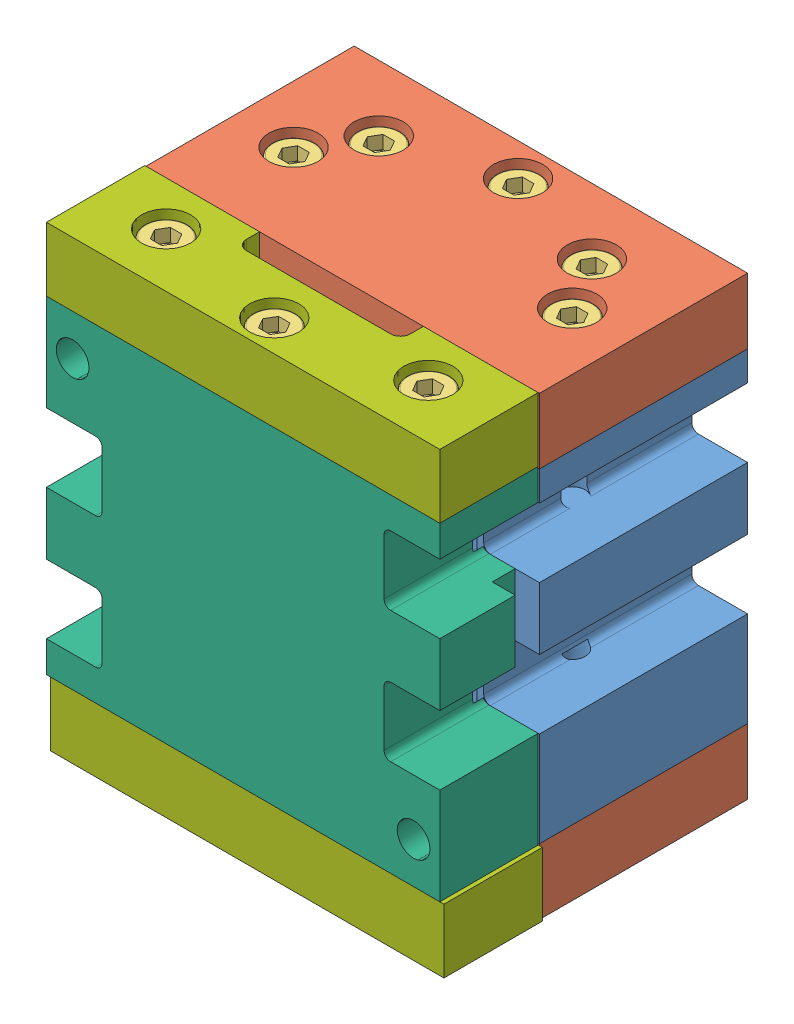
SolidWorks assembly ГТК СБ 00.00.00 Матрица, configuration По умолчанию. Lengths in mm.
Overall size (121.25 139 93.5).
28 component instances, 7 part files, 3 mates.
Components (placement in the parent):
- ГТК 01.01.00 Сборка пресс-формы-1: ГТК 01.01.00 Сборка пресс-формы [По умолчанию] at origin size (120 139 88.5)
  - ГТК 01.01.01 Матрица-1: ГТК 01.01.01 Матрица [По умолчанию] at origin size (120 99 63.5)
  - ГТК 01.01.02 Боковина пресс-формы-1: ГТК 01.01.02 Боковина пресс-формы [По умолчанию] at (0 -49.5 31.75) x (1 0 0) z (0 -1 0) size (120 63.5 20)
  - ISO 4762 М8x16-1: ISO 4762 М8x16 [ISO 4762 M8 x 16 - 16N] at (-42.5 -67.5 36) x (0 1 0) z (0 0 1) size (24 13 13)
  - ISO 4762 М8x16-2: ISO 4762 М8x16 [ISO 4762 M8 x 16 - 16N] at (-32.5 -67.5 20) x (0 1 0) z (0 0 1) size (24 13 13)
  - ISO 4762 М8x16-3: ISO 4762 М8x16 [ISO 4762 M8 x 16 - 16N] at (0 -67.5 10) x (0 1 0) z (0 0 1) size (24 13 13)
  - ISO 4762 М8x16-4: ISO 4762 М8x16 [ISO 4762 M8 x 16 - 16N] at (32.5 -67.5 20) x (0 1 0) z (0 0 1) size (24 13 13)
  - ISO 4762 М8x16-5: ISO 4762 М8x16 [ISO 4762 M8 x 16 - 16N] at (42.5 -67.5 36) x (0 1 0) z (0 0 1) size (24 13 13)
  - ISO 4762 М8x16-11: ISO 4762 М8x16 [ISO 4762 M8 x 16 - 16N] at (-42.5 67.5 36) x (0 -1 0) z (0 0 1) size (24 13 13)
  - ISO 4762 М8x16-12: ISO 4762 М8x16 [ISO 4762 M8 x 16 - 16N] at (-32.5 67.5 20) x (0 -1 0) z (0 0 1) size (24 13 13)
  - ISO 4762 М8x16-13: ISO 4762 М8x16 [ISO 4762 M8 x 16 - 16N] at (0 67.5 10) x (0 -1 0) z (0 0 1) size (24 13 13)
  - ISO 4762 М8x16-14: ISO 4762 М8x16 [ISO 4762 M8 x 16 - 16N] at (32.5 67.5 20) x (0 -1 0) z (0 0 1) size (24 13 13)
  - ISO 4762 М8x16-15: ISO 4762 М8x16 [ISO 4762 M8 x 16 - 16N] at (42.5 67.5 36) x (0 -1 0) z (0 0 1) size (24 13 13)
  - ГТК 01.01.02 Боковина пресс-формы-3: ГТК 01.01.02 Боковина пресс-формы [По умолчанию] at (0 49.5 31.75) x (-1 0 0) z (0 1 0) size (120 63.5 20)
  - ГТК 01.01.03 Направляющая-1: ГТК 01.01.03 Направляющая [По умолчанию] at (-52.375 37.5 33.5) x (0 0 1) z (-0.953769 -0.300541 0) size (55 10 10)
  - ГТК 01.01.03 Направляющая-2: ГТК 01.01.03 Направляющая [По умолчанию] at (51.625 -37.5 33.5) x (0 0 1) z (-0.599492 0.800381 0) size (55 10 10)
  - ГТК 01.01.04 Втулка-1: ГТК 01.01.04 Втулка [По умолчанию] at (0 27 30) x (0 0 1) z (-0.845392 0.534146 0) size (36.5 12 12)
  - ГТК 01.01.04 Втулка-2: ГТК 01.01.04 Втулка [По умолчанию] at (0 -27 30) x (0 0 1) z (-0.844306 0.535861 0) size (36.5 12 12)
- ГТК 01.02.00 Сборка пуансона-1: ГТК 01.02.00 Сборка пуансона [По умолчанию] at (-60.375 -50 63.5) size (121.25 139 30.34)
  - ГТК 01.02.01 Пуансон-1: ГТК 01.02.01 Пуансон [По умолчанию] at origin size (120 100 30)
  - ГТК 02.01.02 Боковина Пуансона-1: ГТК 02.01.02 Боковина Пуансона [По умолчанию] at (121.25 0 30) x (-1 0 0) z (0 -1 0) size (120 30.34 139)
  - ГТК 02.01.02 Боковина Пуансона-2: ГТК 02.01.02 Боковина Пуансона [По умолчанию] at (0 100 30) x (1 0 0) z (0 1 0) size (120 30.34 139)
  - ISO 4762 М8x16-2: ISO 4762 М8x16 [ISO 4762 M8 x 16 - 16N] at (101.25 -17.5 13.5) x (0 1 0) z (0 0 1) size (24 13 13)
  - ISO 4762 М8x16-3: ISO 4762 М8x16 [ISO 4762 M8 x 16 - 16N] at (61.25 -17.5 20.5) x (0 1 0) z (0 0 1) size (24 13 13)
  - ISO 4762 М8x16-4: ISO 4762 М8x16 [ISO 4762 M8 x 16 - 16N] at (21.25 -17.5 13.5) x (0 1 0) z (0 0 1) size (24 13 13)
  - ISO 4762 М8x16-5: ISO 4762 М8x16 [ISO 4762 M8 x 16 - 16N] at (20 117.5 13.5) x (0 -1 0) z (0 0 1) size (24 13 13)
  - ISO 4762 М8x16-6: ISO 4762 М8x16 [ISO 4762 M8 x 16 - 16N] at (60 117.5 20.5) x (0 -1 0) z (0 0 1) size (24 13 13)
  - ISO 4762 М8x16-7: ISO 4762 М8x16 [ISO 4762 M8 x 16 - 16N] at (100 117.5 13.5) x (0 -1 0) z (0 0 1) size (24 13 13)
Mates (geometry in assembly coordinates):
- Концентричный1: concentric aligned: cylinder of Матрица в сборе-1/КОнус-1 through (-52.375 37.5 33.5) axis (0 0 -1) radius 5; cylinder of Сборка пуансона-1/Пуансон-1 through (-52.375 37.5 113.5) axis (0 0 -1) radius 5
- Концентричный2: concentric aligned: cylinder of Матрица в сборе-1/КОнус-2 through (51.625 -37.5 33.5) axis (0 0 -1) radius 5; cylinder of Сборка пуансона-1/Пуансон-1 through (51.625 -37.5 113.5) axis (0 0 -1) radius 5
- Граничное расстояние1: limit distance = 0 mm anti-aligned: plane of Сборка пуансона-1/Пуансон-1 through (-60.375 -50 63.5) normal (0 0 -1); plane of Матрица в сборе-1/Матрица-1 through (0 0 63.5) normal (0 0 1)
